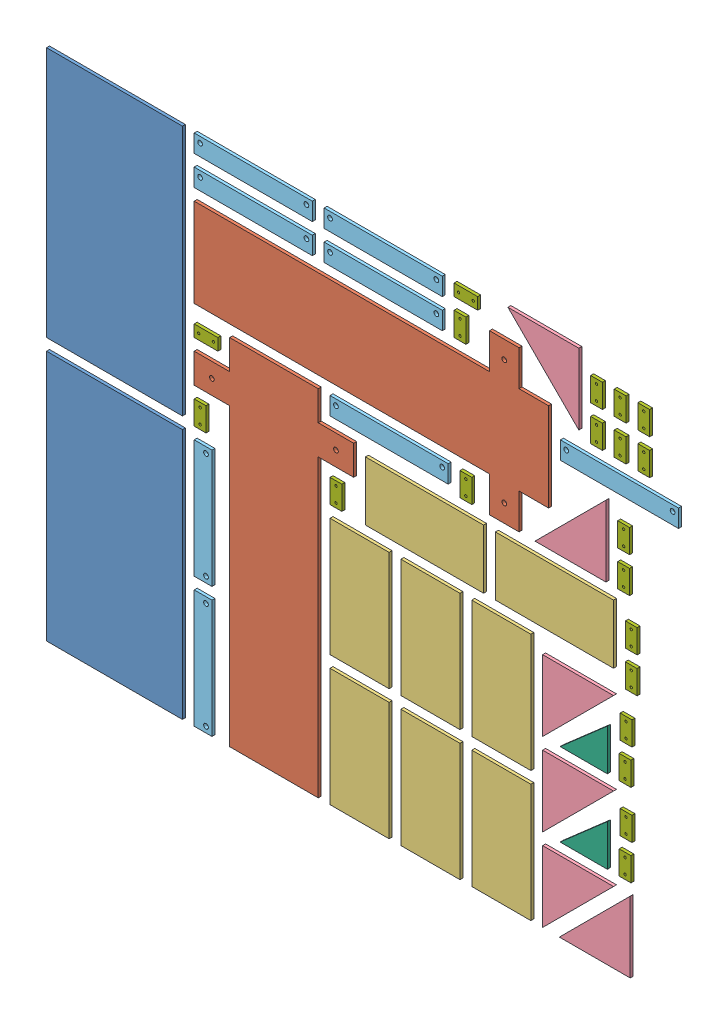
SolidWorks assembly New_Nesting(5mm), configuration Layout1[Steel_5mm_Qnty1]. Lengths in mm.
Overall size (1800 900 5).
48 component instances, 7 part files, 0 mates.
Components (placement in the parent):
- Z_Plate_2-1: Z_Plate_2 [Default] at (125 227.5 0) x (1 0 0) z (0 0 -1) size (230 425 5)
- Z_Plate_2-2: Z_Plate_2 [Default] at (125 672.5 0) x (1 0 0) z (0 0 -1) size (230 425 5)
- Z_Plate_1-1: Z_Plate_1 [Default] at (395 310 0) x (1 0 0) z (0 0 -1) size (270 600 5)
- Z_Plate_1-2: Z_Plate_1 [Default] at (560 705 0) x (0 -1 0) z (0 0 -1) size (270 600 5)
- C Covering 1-1: C Covering 1 [Default] at (540 110 0) x (0 -1 0) z (0 0 -1) size (200 100 5)
- C Covering 1-2: C Covering 1 [Default] at (540 330 0) x (0 -1 0) z (0 0 -1) size (200 100 5)
- C Covering 1-3: C Covering 1 [Default] at (650 500 0) x (1 0 0) z (0 0 -1) size (200 100 5)
- C Covering 1-4: C Covering 1 [Default] at (660 110 0) x (0 -1 0) z (0 0 -1) size (200 100 5)
- C Covering 1-5: C Covering 1 [Default] at (660 330 0) x (0 -1 0) z (0 0 -1) size (200 100 5)
- C Covering 1-6: C Covering 1 [Default] at (780 110 0) x (0 -1 0) z (0 0 -1) size (200 100 5)
- C Covering 1-7: C Covering 1 [Default] at (780 330 0) x (0 -1 0) z (0 0 -1) size (200 100 5)
- C Covering 1-8: C Covering 1 [Default] at (870 500 0) x (1 0 0) z (0 0 -1) size (200 100 5)
- Motor Extension Rib-1: Motor Extension Rib [Default] at (911.2132 890 0) x (0 -1 0) z (0 0 -1) size (120 120 5)
- Motor Extension Rib-2: Motor Extension Rib [Default] at (850 130 0) x (1 0 0) z (0 0 -1) size (120 120 5)
- Motor Extension Rib-3: Motor Extension Rib [Default] at (850 270 0) x (1 0 0) z (0 0 -1) size (120 120 5)
- Motor Extension Rib-4: Motor Extension Rib [Default] at (850 410 0) x (1 0 0) z (0 0 -1) size (120 120 5)
- Motor Extension Rib-5: Motor Extension Rib [Default] at (957.0711 570 0) x (-1 0 0) z (0 0 -1) size (120 120 5)
- Motor Extension Rib-6: Motor Extension Rib [Default] at (998.2843 10 0) x (-1 0 0) z (0 0 -1) size (120 120 5)
- C Covering 2-1: C Covering 2 [Default] at (275 110 0) x (0 -1 0) z (0 0 -1) size (200 30 5)
- C Covering 2-2: C Covering 2 [Default] at (275 330 0) x (0 -1 0) z (0 0 -1) size (200 30 5)
- C Covering 2-3: C Covering 2 [Default] at (360 815 0) x (1 0 0) z (0 0 -1) size (200 30 5)
- C Covering 2-4: C Covering 2 [Default] at (360 865 0) x (1 0 0) z (0 0 -1) size (200 30 5)
- C Covering 2-5: C Covering 2 [Default] at (580 815 0) x (1 0 0) z (0 0 -1) size (200 30 5)
- C Covering 2-6: C Covering 2 [Default] at (580 865 0) x (1 0 0) z (0 0 -1) size (200 30 5)
- C Covering 2-7: C Covering 2 [Default] at (590 595 0) x (1 0 0) z (0 0 -1) size (200 30 5)
- C Covering 2-8: C Covering 2 [Default] at (980 725 0) x (1 0 0) z (0 0 -1) size (200 30 5)
- Rib-1: Rib [Default] at (959.5205 150 0) x (0 0 -1) z (1 0 0) size (5 70 80)
- Rib-2: Rib [Default] at (959.5205 290 0) x (0 0 -1) z (1 0 0) size (5 70 80)
- Bracket_Plate-1: Bracket_Plate [Default] at (270 470 0) x (0 -1 0) z (1 0 0) size (40 5 20)
- Bracket_Plate-2: Bracket_Plate [Default] at (280 590 0) x (1 0 0) z (0 1 0) size (40 5 20)
- Bracket_Plate-3: Bracket_Plate [Default] at (500 470 0) x (0 -1 0) z (1 0 0) size (40 5 20)
- Bracket_Plate-4: Bracket_Plate [Default] at (710 820 0) x (0 -1 0) z (1 0 0) size (40 5 20)
- Bracket_Plate-5: Bracket_Plate [Default] at (720 590 0) x (0 -1 0) z (1 0 0) size (40 5 20)
- Bracket_Plate-6: Bracket_Plate [Default] at (720 870 0) x (1 0 0) z (0 1 0) size (40 5 20)
- Bracket_Plate-7: Bracket_Plate [Default] at (941.2132 780 0) x (0 -1 0) z (1 0 0) size (40 5 20)
- Bracket_Plate-8: Bracket_Plate [Default] at (941.2132 840 0) x (0 -1 0) z (1 0 0) size (40 5 20)
- Bracket_Plate-9: Bracket_Plate [Default] at (981.2132 780 0) x (0 -1 0) z (1 0 0) size (40 5 20)
- Bracket_Plate-10: Bracket_Plate [Default] at (981.2132 840 0) x (0 -1 0) z (1 0 0) size (40 5 20)
- Bracket_Plate-11: Bracket_Plate [Default] at (987.0711 590 0) x (0 -1 0) z (1 0 0) size (40 5 20)
- Bracket_Plate-12: Bracket_Plate [Default] at (987.0711 650 0) x (0 -1 0) z (1 0 0) size (40 5 20)
- Bracket_Plate-13: Bracket_Plate [Default] at (989.5205 170 0) x (0 -1 0) z (1 0 0) size (40 5 20)
- Bracket_Plate-14: Bracket_Plate [Default] at (989.5205 310 0) x (0 -1 0) z (1 0 0) size (40 5 20)
- Bracket_Plate-15: Bracket_Plate [Default] at (991.2132 230 0) x (0 -1 0) z (1 0 0) size (40 5 20)
- Bracket_Plate-16: Bracket_Plate [Default] at (991.2132 370 0) x (0 -1 0) z (1 0 0) size (40 5 20)
- Bracket_Plate-17: Bracket_Plate [Default] at (1000 449.5615 0) x (0 -1 0) z (1 0 0) size (40 5 20)
- Bracket_Plate-18: Bracket_Plate [Default] at (1000 509.5615 0) x (0 -1 0) z (1 0 0) size (40 5 20)
- Bracket_Plate-19: Bracket_Plate [Default] at (1021.2132 780 0) x (0 -1 0) z (1 0 0) size (40 5 20)
- Bracket_Plate-20: Bracket_Plate [Default] at (1021.2132 840 0) x (0 -1 0) z (1 0 0) size (40 5 20)
